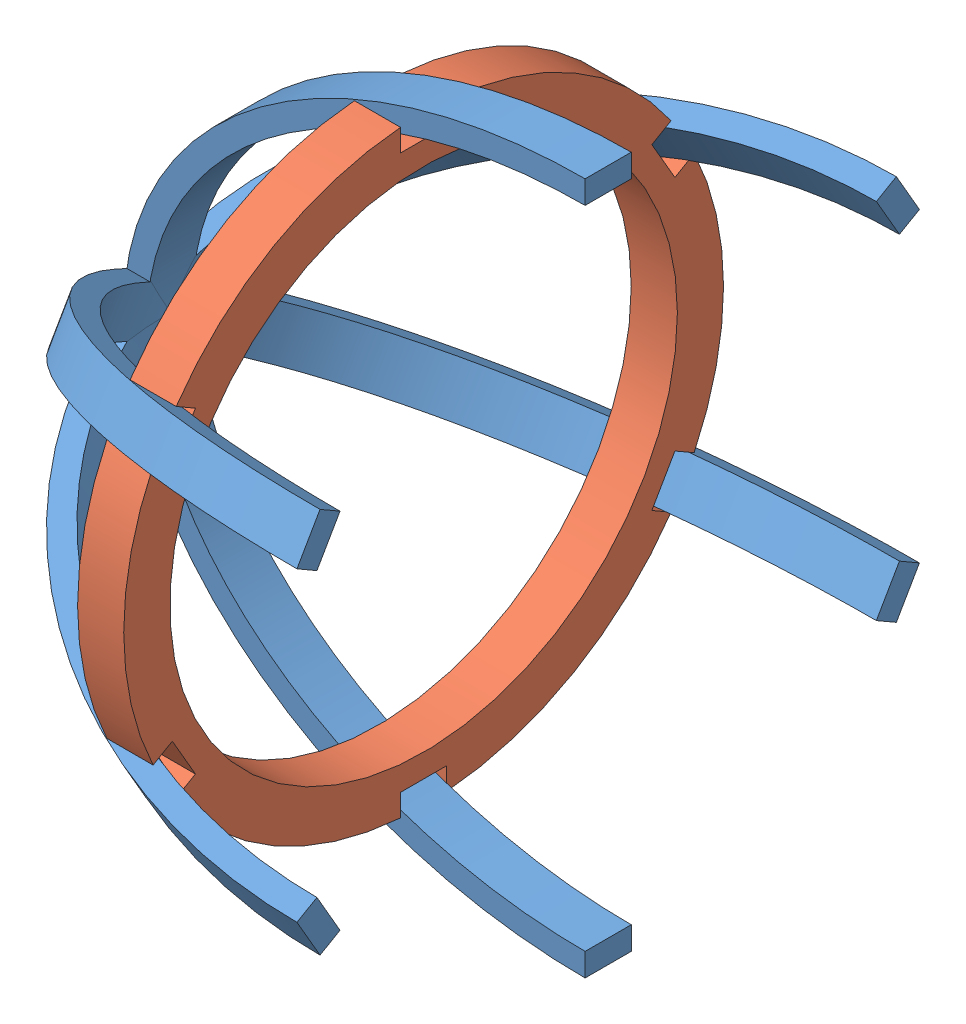
SolidWorks assembly front_back, configuration Predeterminado. Lengths in mm.
Overall size (100 150 134.9).
7 component instances, 2 part files, 18 mates.
Components (placement in the parent):
- beam2-1: beam2 [Predeterminado] at (-8.5023 -14.6311 100) size (100 75 10)
- circle_small-1: circle_small [Predeterminado] at (-58.5023 -14.7805 105) x (0 0 -1) z (1 0 0) size (130 129.61 10)
- beam2-2: beam2 [Predeterminado] at (-8.5023 -14.6311 110) x (1 0 0) z (0 0 -1) size (100 75 10)
- beam2-3: beam2 [Predeterminado] at (-8.5023 -19.1106 102.5) x (1 0 0) z (0 0.866025 0.5) size (100 75 10)
- beam2-4: beam2 [Predeterminado] at (-8.5023 -10.4503 107.5) x (1 0 0) z (0 -0.866025 -0.5) size (100 75 10)
- beam2-5: beam2 [Predeterminado] at (-8.5023 -10.4503 102.5) x (1 0 0) z (0 -0.866025 0.5) size (100 75 10)
- beam2-6: beam2 [Predeterminado] at (-8.5023 -19.1106 107.5) x (1 0 0) z (0 0.866025 -0.5) size (100 75 10)
Mates (geometry in assembly coordinates):
- Distance2: distance = 40 mm aligned: plane of beam2-1 through (-8.5023 60.3689 110) normal (1 0 0); plane of circle_small-1 through (-48.5023 -14.7805 105) normal (1 0 0)
- Coincident3: coincident anti-aligned: plane of beam2-1 through (-76.213 34.4019 100) normal (0 0 -1); plane of circle_small-1 through (-58.5023 45.2195 100) normal (0 0 1)
- Parallel3: parallel: line of assembly; face of beam2-1; line of circle_small-1 through (-48.5023 45.2195 110) axis (0 0 -1)
- Coincident4: coincident anti-aligned: plane of beam2-1 through (-108.5023 -14.6311 110) normal (0 -1 0); plane of beam2-2 through (-108.5023 -14.6311 100) normal (0 1 0)
- Coincident5: coincident anti-aligned: line of beam2-1 through (-108.5023 -14.6311 110) axis (0 0 -1); line of beam2-2 through (-108.5023 -14.6311 100) axis (0 0 1)
- Coincident6: coincident aligned: line of beam2-1 through (-108.5023 -14.6311 110) axis (1 0 0); line of beam2-2 through (-108.5023 -14.6311 110) axis (1 0 0)
- Coincident7: coincident anti-aligned: plane of beam2-5 through (-108.5023 -19.1106 107.5) normal (0 -0.5 -0.866025); plane of beam2-6 through (-108.5023 -10.4503 102.5) normal (0 0.5 0.866025)
- Coincident9: coincident aligned: plane of beam2-5 through (-76.213 14.0662 144.9638) normal (0 0.866025 -0.5); plane of beam2-6 through (-76.213 -34.9668 60.0362) normal (0 0.866025 -0.5)
- Parallel4: parallel: face of beam2-5; face of beam2-6
- Coincident10: coincident anti-aligned: line of beam2-5 through (-108.5023 -19.1106 107.5) axis (0 0.866025 -0.5); line of beam2-6 through (-108.5023 -10.4503 102.5) axis (0 -0.866025 0.5)
- Coincident14: coincident anti-aligned: plane of beam2-3 through (-108.5023 -10.4503 107.5) normal (0 -0.5 0.866025); plane of beam2-4 through (-108.5023 -19.1106 102.5) normal (0 0.5 -0.866025)
- Coincident15: coincident aligned: plane of beam2-3 through (-76.213 14.0662 65.0362) normal (0 0.866025 0.5); plane of beam2-4 through (-76.213 -34.9668 149.9638) normal (0 0.866025 0.5)
- Coincident16: coincident anti-aligned: line of beam2-3 through (-103.5023 -10.4503 107.5) axis (0 -0.866025 -0.5); line of beam2-4 through (-103.5023 -19.1106 102.5) axis (0 0.866025 0.5)
- Coincident17: coincident anti-aligned: plane of circle_small-1 through (-58.5023 10.8894 159.4615) normal (0 0.866025 -0.5); plane of beam2-5 through (-76.213 5.4059 149.9638) normal (0 -0.866025 0.5)
- Distance3: distance = 40 mm aligned: plane of beam2-6 through (-8.5023 -47.9503 37.5481) normal (1 0 0); plane of circle_small-1 through (-48.5023 -14.7805 105) normal (1 0 0)
- Coincident20: coincident: point of beam2-5; edge_curve of beam2-6
- Coincident24: coincident anti-aligned: plane of circle_small-1 through (-58.5023 10.8894 50.5385) normal (0 0.866025 0.5); plane of beam2-3 through (-76.213 5.4059 60.0362) normal (0 -0.866025 -0.5)
- Coincident25: coincident: unknown of beam2-3; unknown of beam2-6
